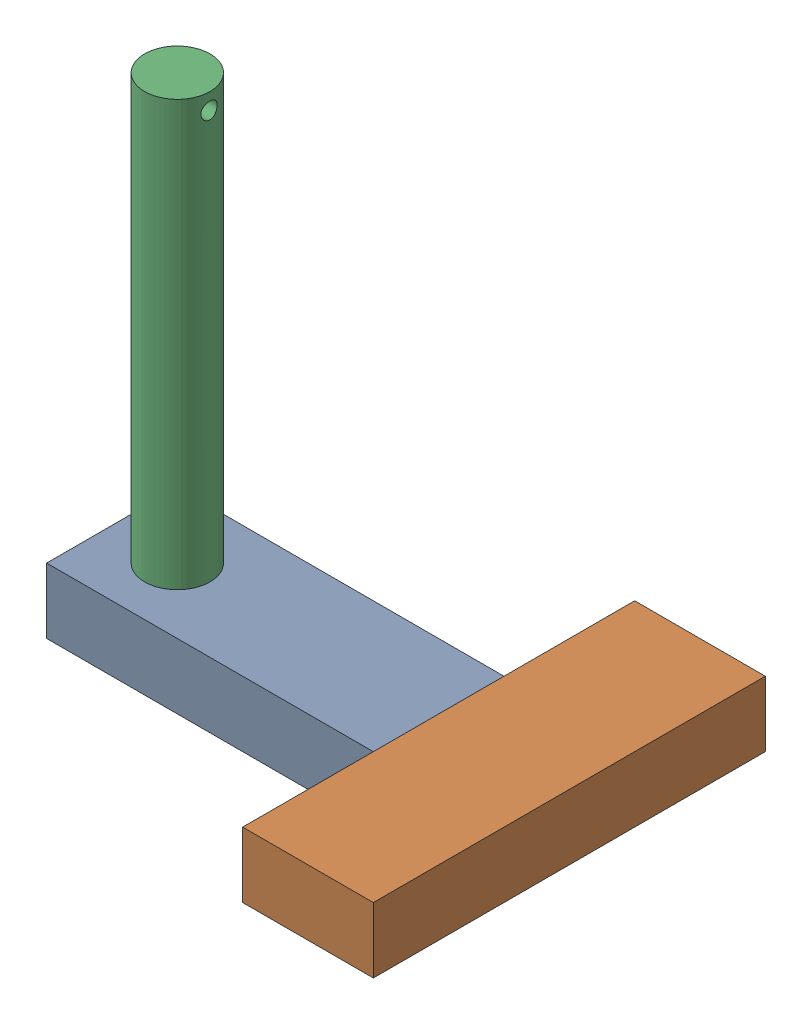
SolidWorks assembly 01-077-00-0, configuration Default. Lengths in mm.
Overall size (177.8 190.5 152.4).
3 component instances, 3 part files, 0 mates.
Components (placement in the parent):
- 01-044-00-0-1: 01-044-00-0 [Default] at origin size (127 25.4 50.8)
- 01-045-00-0-1: 01-045-00-0 [Default] at (177.8 0 50.8) x (0 0 -1) z (1 0 0) size (152.4 25.4 50.8)
- 01-046-00-0-1: 01-046-00-0 [Default] at (25.4 6.35 -25.4) size (25.4 184.15 25.4)
